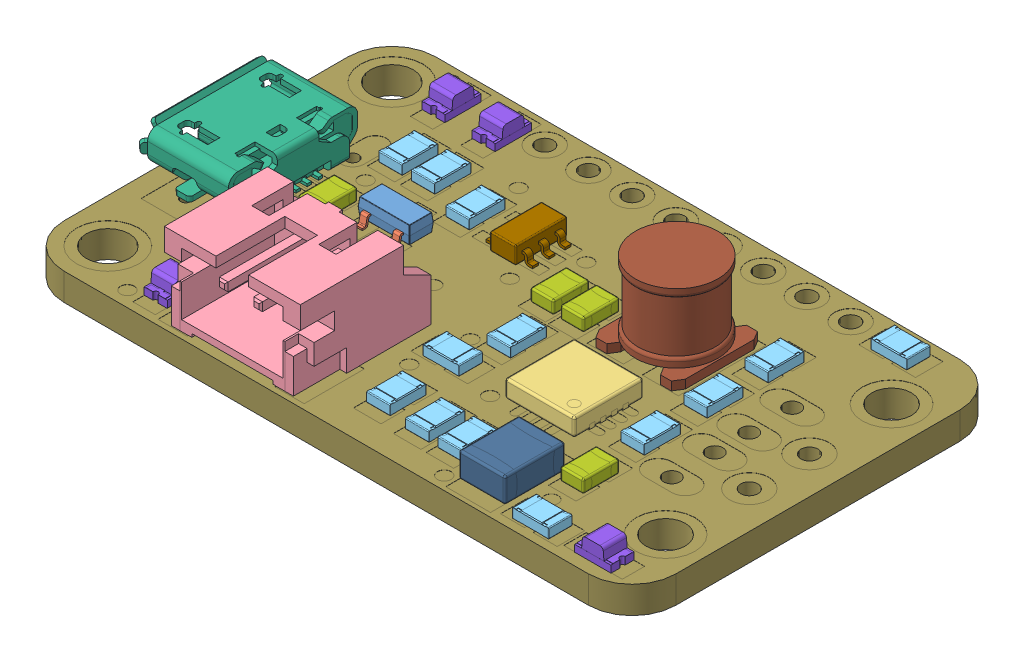
SolidWorks assembly PowerBoost 500C v24, configuration Default. Lengths in mm.
Overall size (35.64 6.37 21.59).
35 component instances, 12 part files, 0 mates.
Components (placement in the parent):
- PowerBoost 500C v24.step-1: PowerBoost 500C v24.step [Default] at origin size (35.64 6.37 21.59)
  - sot23.step-1: sot23.step [Default] at (9.906 1.57 -11.911) x (1 0 0) z (0 1 0) size (3 2.4 1.1)
    - Component1.step-1: Component1.step [Default] at origin size (3 1.4 1)
    - pin.step-1: pin.step [Default] at origin size (0.4 0.55 0.6)
    - pin.step-2: pin.step [Default] at (1.9 0 0) size (0.4 0.55 0.6)
    - pin.step-3: pin.step [Default] at (-0.95 0 0) x (-1 0 0) z (0 0 1) size (0.4 0.55 0.6)
  - MO-229W3030D-1_4000.step-1: MO-229W3030D-1_4000.step [Default] at (23.763 1.57 -8.428) x (0 0 -1) z (0 1 0) size (4.03 4.03 1.04)
  - Molex2pinSMD.step-1: Molex2pinSMD.step [Default] at (11.938 1.57 -0.381) size (7.9 4.8 8.6)
  - RESC-0805.step-1: RESC-0805.step [Default] at (6.8577 1.55 -15.6975) x (0 0 -1) z (0 1 0) size (2.1 1.35 0.6)
  - RESC-0805.step-2: RESC-0805.step [Default] at (8.7577 1.55 -15.6975) x (0 0 -1) z (0 1 0) size (2.1 1.35 0.6)
  - RESC-0805.step-3: RESC-0805.step [Default] at (11.5577 1.55 -14.8975) x (0 0 -1) z (0 1 0) size (2.1 1.35 0.6)
  - RESC-0805.step-4: RESC-0805.step [Default] at (6.8777 1.55 -6.7475) x (0 0 -1) z (0 1 0) size (2.1 1.35 0.6)
  - RESC-0805.step-5: RESC-0805.step [Default] at (19.2077 1.55 -9.6475) x (0 0 -1) z (0 1 0) size (2.1 1.35 0.6)
  - RESC-0805.step-6: RESC-0805.step [Default] at (18.2573 1.55 -6.8672) x (-1 0 0) z (0 1 0) size (2.1 1.35 0.6)
  - MicroUSB.step-1: MicroUSB.step [Default] at (25.7335 0.77 27.105) x (0 0 1) z (0 1 0) size (7.98 5.43 2.76)
  - RESC-0805.step-7: RESC-0805.step [Default] at (18.6077 1.55 -3.2475) x (0 0 -1) z (0 1 0) size (2.1 1.35 0.6)
  - RESC-0805.step-8: RESC-0805.step [Default] at (21.0777 1.55 -3.0375) x (0 0 -1) z (0 1 0) size (2.1 1.35 0.6)
  - RESC-0805.step-9: RESC-0805.step [Default] at (22.9627 1.55 -3.0375) x (0 0 -1) z (0 1 0) size (2.1 1.35 0.6)
  - RESC-0805.step-10: RESC-0805.step [Default] at (27.9477 1.55 -15.8875) x (0 0 -1) z (0 1 0) size (2.1 1.35 0.6)
  - RESC-0805.step-11: RESC-0805.step [Default] at (27.9477 1.55 -12.3375) x (0 0 -1) z (0 1 0) size (2.1 1.35 0.6)
  - RESC-0805.step-12: RESC-0805.step [Default] at (27.9877 1.55 -8.6475) x (0 0 -1) z (0 1 0) size (2.1 1.35 0.6)
  - RESC-0805.step-13: RESC-0805.step [Default] at (29.0573 1.55 -1.2797) x (-1 0 0) z (0 1 0) size (2.1 1.35 0.6)
  - RESC-0805.step-14: RESC-0805.step [Default] at (30.9573 1.55 -20.1997) x (-1 0 0) z (0 1 0) size (2.1 1.35 0.6)
  - CAPC-0805-T0.step-1: CAPC-0805-T0.step [Default] at (28.194 2.32 -4.903) x (0 0 -1) z (0 -1 0) size (2.1 1.35 0.75)
  - CAPC-0805-T0.step-2: CAPC-0805-T0.step [Default] at (20.064 2.32 -13.043) x (0 0 -1) z (0 -1 0) size (2.1 1.35 0.75)
  - CAPC-0805-T0.step-3: CAPC-0805-T0.step [Default] at (18.314 2.32 -13.043) x (0 0 -1) z (0 -1 0) size (2.1 1.35 0.75)
  - CAPC-0805-T0.step-4: CAPC-0805-T0.step [Default] at (6.894 2.32 -10.973) x (0 0 -1) z (0 -1 0) size (2.1 1.35 0.75)
  - LED-0805H1.step-1: LED-0805H1.step [Default] at (31.681 1.55 -1.365) x (1 0 0) z (0 1 0) size (2.1 1.35 1.1)
  - LED-0805H1.step-2: LED-0805H1.step [Default] at (6.731 1.55 -1.28) x (0 0 -1) z (0 1 0) size (2.1 1.35 1.1)
  - LED-0805H1.step-3: LED-0805H1.step [Default] at (5.461 1.55 -18.7) x (0 0 -1) z (0 1 0) size (2.1 1.35 1.1)
  - LED-0805H1.step-4: LED-0805H1.step [Default] at (8.376 1.55 -18.7) x (0 0 -1) z (0 1 0) size (2.1 1.35 1.1)
  - TSOP-5 v4.step-1: TSOP-5 v4.step [Default] at (14.6807 1.5593 -14.859) x (0 0 -1) z (0 1 0) size (3 2.71 1.05)
  - cap.step-1: cap.step [Default] at (25.8 1.575 -2.775) x (0 0 -1) z (0 1 0) size (3.5 2.7 1.45)
  - VLC5045.step-1: VLC5045.step [Default] at (21.521 1.57 -16.626) size (5 4.5 5)
  - PowerBoost 500C.step-1: PowerBoost 500C.step [Default] at origin size (35.56 1.58 21.59)
